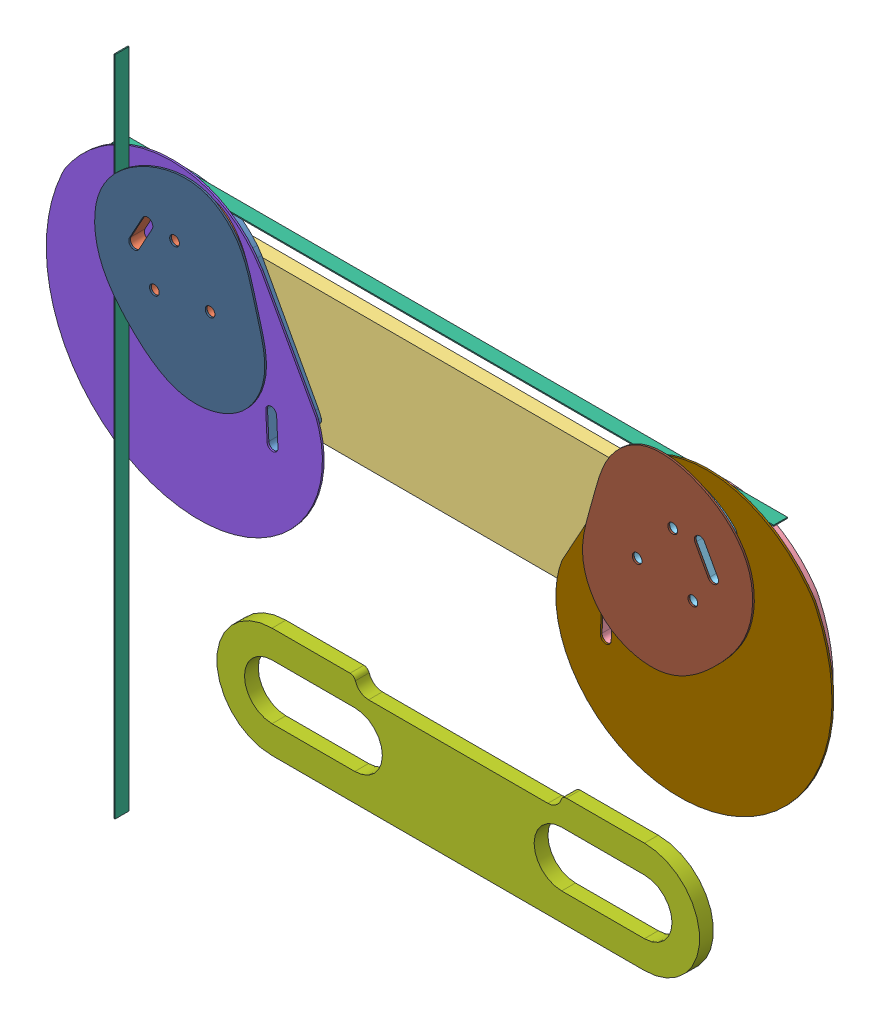
SolidWorks assembly cam_assembly_STS, configuration Default. Lengths in mm.
Overall size (406.79 304.8 22.29).
12 component instances, 11 part files, 23 mates.
Components (placement in the parent):
- outer_cam-1: outer_cam [Default] at (-101.6 0 7.175) x (-0.356727 -0.934209 0) z (0 0 1) size (114.45 118.23 8)
- inner_cam-1: inner_cam [Default] at (-101.6 0 15.1437) x (-0.356727 -0.934209 0) z (0 0 1) size (67.19 67.49 6.35)
- cam_backing-1: cam_backing [Default] at origin size (263.2 60 6.35)
- Mirrorouter_cam-2: Mirrorouter_cam [Default] at (101.6 0 7.175) x (0.356727 -0.934209 0) z (0 0 -1) size (114.45 118.23 8)
- Mirrorinner_cam-3: Mirrorinner_cam [Default] at (101.6 0 15.1437) x (0.356727 -0.934209 0) z (0 0 -1) size (67.19 67.49 6.35)
- elastic_band_between-2: elastic_band_between [Default] at (0 47.8989 7.175) x (-1 0 0) z (0 0 1) size (304.8 0.5 6.35)
- elastic_band_between-3: elastic_band_between [Default] at (-143.0725 -60.2661 15.1437) x (0 -1 0) z (0 0 1) size (304.8 0.5 6.35)
- pull_handle-1: pull_handle [Default] at (0 -140.9587 0) x (1 0 0) z (0 -1 0) size (222.25 6.35 50.8)
- outer_cam_cover-1: outer_cam_cover [Default] at (-101.6 0 11.5719) x (-0.356727 -0.934209 0) z (0 0 1) size (132.94 135.35 0.79)
- Mirrorouter_cam_cover-2: Mirrorouter_cam_cover [Default] at (101.6 0 11.5719) x (0.356727 -0.934209 0) z (0 0 -1) size (132.94 135.35 0.79)
- inner_cam_cover-1: inner_cam_cover [Default] at (-101.6 0 18.7156) x (-0.356727 -0.934209 0) z (0 0 1) size (91.94 90.36 0.79)
- Mirrorinner_cam_cover-2: Mirrorinner_cam_cover [Default] at (101.6 0 18.7156) x (0.356727 -0.934209 0) z (0 0 -1) size (91.94 90.36 0.79)
Mates (geometry in assembly coordinates):
- Coincident1: coincident aligned: plane of outer_cam-1 through (-101.6 0 7.175) normal (0.934209 -0.356727 0); plane of inner_cam-1 through (-101.6 0 15.1437) normal (0.934209 -0.356727 0)
- Coincident2: coincident aligned: plane of outer_cam-1 through (-101.6 0 7.175) normal (0.934209 -0.356727 0); plane of inner_cam-1 through (-101.6 0 15.1437) normal (0.934209 -0.356727 0)
- Coincident3: coincident aligned: plane of outer_cam-1 through (-101.6 0 7.175) normal (-0.356727 -0.934209 0); plane of inner_cam-1 through (-101.6 0 15.1437) normal (-0.356727 -0.934209 0)
- Coincident5: coincident aligned: plane of cam_backing-1 through (0 0 0) normal (0 0 1)
- Coincident6: coincident aligned: plane of cam_backing-1 through (0 0 0) normal (0 1 0)
- Coincident7: coincident aligned: plane of cam_backing-1 through (0 0 0) normal (1 0 0)
- Coincident10: coincident anti-aligned: plane of outer_cam-1 through (-101.6 0 3.175) normal (0 0 -1); plane of cam_backing-1 through (-101.6 0 3.175) normal (0 0 1)
- Concentric2: concentric aligned: cylinder of outer_cam-1 through (-101.6 0 11.175) axis (0 0 -1) radius 3.175; cylinder of cam_backing-1 through (-101.6 0 3.175) axis (0 0 -1) radius 6.35
- Coincident12: coincident aligned: plane of outer_cam-1 through (-101.6 0 7.175) normal (0 0 1); plane of elastic_band_between-2 through (0 47.8989 7.175) normal (0 0 1)
- CamMateTangent1: cam tangent: plane of assembly; face of outer_cam-1; plane of elastic_band_between-2 through (0 48.1489 7.175) normal (0 1 0)
- CamMateTangent2: cam tangent: plane of assembly; face of inner_cam-1; plane of elastic_band_between-3 through (-143.3225 -60.2661 15.1437) normal (-1 0 0)
- Coincident15: coincident anti-aligned: plane of elastic_band_between-2 through (0 47.8989 7.175) normal (-1 0 0)
- Parallel3: parallel anti-aligned: plane of elastic_band_between-3 through (-143.3225 -60.2661 15.1437) normal (-1 0 0)
- Coincident18: coincident aligned: plane of inner_cam-1 through (-101.6 0 15.1437) normal (0 0 1); plane of elastic_band_between-3 through (-143.0725 -60.2661 15.1437) normal (0 0 1)
- Coincident19: coincident aligned: plane of cam_backing-1 through (-101.6 0 3.175) normal (0 0 1); plane of pull_handle-1 through (-85.725 -140.9587 3.175) normal (0 0 1)
- Coincident20: coincident aligned: line of cam_backing-1 through (60 0 30) axis (0 0 -1); line of pull_handle-1 through (0 -115.5587 0) axis (0 -1 0)
- Coincident21: coincident anti-aligned: plane of outer_cam-1 through (-101.6 0 11.175) normal (0 0 1); plane of outer_cam_cover-1 through (-101.6 0 11.175) normal (0 0 -1)
- Concentric3: concentric aligned: cylinder of outer_cam-1 through (-98.2963 12.2193 11.175) axis (0 0 1) radius 1.65; cylinder of outer_cam_cover-1 through (-98.2963 12.2193 11.9688) axis (0 0 1) radius 2.25
- Concentric4: concentric aligned: cylinder of outer_cam-1 through (-114.682 32.3814 11.175) axis (0 0 1) radius 1.65; cylinder of outer_cam_cover-1 through (-114.682 32.3814 11.9688) axis (0 0 1) radius 2.25
- Coincident22: coincident anti-aligned: plane of inner_cam-1 through (-111.8867 51.3882 11.9688) normal (0 0 -1); plane of outer_cam_cover-1 through (-101.6 0 11.9688) normal (0 0 1)
- Coincident23: coincident anti-aligned: plane of inner_cam-1 through (-111.8867 51.3882 18.3188) normal (0 0 1); plane of inner_cam_cover-1 through (-137.2838 49.7625 18.3188) normal (0 0 -1)
- Concentric5: concentric aligned: cylinder of inner_cam-1 through (-114.682 32.3814 18.3188) axis (0 0 1) radius 2.25; cylinder of inner_cam_cover-1 through (-114.682 32.3814 19.1125) axis (0 0 1) radius 2.25
- Concentric6: concentric aligned: cylinder of inner_cam-1 through (-98.2963 12.2193 18.3188) axis (0 0 1) radius 2.25; cylinder of inner_cam_cover-1 through (-98.2963 12.2193 19.1125) axis (0 0 1) radius 2.25
